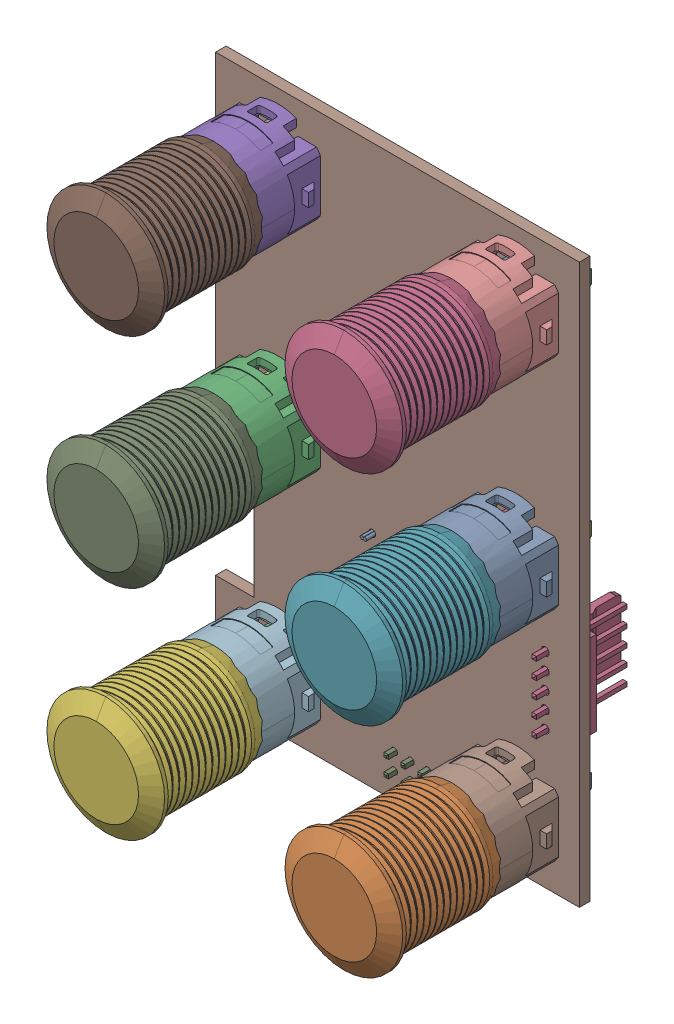
SolidWorks assembly console_left, configuration Default. Lengths in mm.
Overall size (55 84.5 40.9).
107 component instances, 13 part files, 0 mates.
Components (placement in the parent):
- Push Button M16-1: Push Button M16 [Default] at (193 -183 27.15) size (17.8 17.8 33.5)
  - Push Button M16-0-1: Push Button M16-0 [Default] at origin size (17.8 17.8 33.5)
- Push Button M16-2: Push Button M16 [Default] at (193 -216 27.15) size (17.8 17.8 33.5)
  - Push Button M16-0-1: Push Button M16-0 [Default] at origin size (17.8 17.8 33.5)
- Push Button M16-3: Push Button M16 [Default] at (157 -183 27.15) size (17.8 17.8 33.5)
  - Push Button M16-0-1: Push Button M16-0 [Default] at origin size (17.8 17.8 33.5)
- Push Button M16-4: Push Button M16 [Default] at (193 -150 27.15) size (17.8 17.8 33.5)
  - Push Button M16-0-1: Push Button M16-0 [Default] at origin size (17.8 17.8 33.5)
- Push Button M16-5: Push Button M16 [Default] at (157 -150 27.15) size (17.8 17.8 33.5)
  - Push Button M16-0-1: Push Button M16-0 [Default] at origin size (17.8 17.8 33.5)
- Push Button M16-6: Push Button M16 [Default] at (157 -216 27.15) size (17.8 17.8 33.5)
  - Push Button M16-0-1: Push Button M16-0 [Default] at origin size (17.8 17.8 33.5)
- R_1206_3216Metric-1: R_1206_3216Metric [Default] at (189.738 -195.961 -0.05) x (0 1 0) z (0 0 -1) size (3.2 1.6 0.55)
  - R_1206_3216Metric-1-1: R_1206_3216Metric-1 [Default] at origin size (3.2 1.6 0.55)
- R_1206_3216Metric-2: R_1206_3216Metric [Default] at (163.55 -152.908 -0.05) x (-1 0 0) z (0 0 -1) size (3.2 1.6 0.55)
  - R_1206_3216Metric-1-1: R_1206_3216Metric-1 [Default] at origin size (3.2 1.6 0.55)
- R_1206_3216Metric-3: R_1206_3216Metric [Default] at (183.642 -215.9 -0.05) x (0 -1 0) z (0 0 -1) size (3.2 1.6 0.55)
  - R_1206_3216Metric-1-1: R_1206_3216Metric-1 [Default] at origin size (3.2 1.6 0.55)
- R_1206_3216Metric-4: R_1206_3216Metric [Default] at (189.484 -218.974 -0.05) x (0 -1 0) z (0 0 -1) size (3.2 1.6 0.55)
  - R_1206_3216Metric-1-1: R_1206_3216Metric-1 [Default] at origin size (3.2 1.6 0.55)
- R_1206_3216Metric-5: R_1206_3216Metric [Default] at (183.642 -166.09 -0.05) x (0 -1 0) z (0 0 -1) size (3.2 1.6 0.55)
  - R_1206_3216Metric-1-1: R_1206_3216Metric-1 [Default] at origin size (3.2 1.6 0.55)
- R_1206_3216Metric-6: R_1206_3216Metric [Default] at (160.02 -199.491 -0.05) x (0 1 0) z (0 0 -1) size (3.2 1.6 0.55)
  - R_1206_3216Metric-1-1: R_1206_3216Metric-1 [Default] at origin size (3.2 1.6 0.55)
- R_1206_3216Metric-7: R_1206_3216Metric [Default] at (158.75 -165.1 -0.05) x (-1 0 0) z (0 0 -1) size (3.2 1.6 0.55)
  - R_1206_3216Metric-1-1: R_1206_3216Metric-1 [Default] at origin size (3.2 1.6 0.55)
- R_1206_3216Metric-8: R_1206_3216Metric [Default] at (179.451 -149.987 -0.05) x (0 1 0) z (0 0 -1) size (3.2 1.6 0.55)
  - R_1206_3216Metric-1-1: R_1206_3216Metric-1 [Default] at origin size (3.2 1.6 0.55)
- R_1206_3216Metric-9: R_1206_3216Metric [Default] at (183.896 -175.032 -0.05) x (0 1 0) z (0 0 -1) size (3.2 1.6 0.55)
  - R_1206_3216Metric-1-1: R_1206_3216Metric-1 [Default] at origin size (3.2 1.6 0.55)
- C_0603_1608Metric-1: C_0603_1608Metric [Default] at (181.0766 -183.1086 -0.05) x (0 1 0) z (0 0 -1) size (1.6 0.8 0.8)
  - C_0603_1608Metric-2-1: C_0603_1608Metric-2 [Default] at origin size (1.6 0.8 0.8)
- SOIC-14_3.9x8.7mm_P1.27mm-1: SOIC-14_3.9x8.7mm_P1.27mm [Default] at (177.546 -209.296 -0.05) x (0 -1 0) z (0 0 -1) size (6 8.7 1.75)
  - SOIC_14_39x87mm_P127mm-1: SOIC_14_39x87mm_P127mm [Default] at origin size (6 8.7 1.75)
- C_0603_1608Metric-2: C_0603_1608Metric [Default] at (171.704 -207.137 -0.05) x (0 1 0) z (0 0 -1) size (1.6 0.8 0.8)
  - C_0603_1608Metric-2-1: C_0603_1608Metric-2 [Default] at origin size (1.6 0.8 0.8)
- SOT-23-1: SOT-23 [Default] at (185.8495 -220.472 -0.05) x (-1 0 0) z (0 0 -1) size (2.5 3 1.2)
  - SOT_23-1: SOT_23 [Default] at origin size (2.5 3 1.2)
- R_1206_3216Metric-10: R_1206_3216Metric [Default] at (188.24 -185.166 -0.05) x (1 0 0) z (0 0 -1) size (3.2 1.6 0.55)
  - R_1206_3216Metric-1-1: R_1206_3216Metric-1 [Default] at origin size (3.2 1.6 0.55)
- C_1210_3225Metric-1: C_1210_3225Metric [Default] at (161.036 -190.246 -0.05) x (1 0 0) z (0 0 -1) size (3.2 2.5 2.5)
  - C_1210_3225Metric-3-1: C_1210_3225Metric-3 [Default] at origin size (3.2 2.5 2.5)
- R_1206_3216Metric-11: R_1206_3216Metric [Default] at (162.28 -209.296 -0.05) x (-1 0 0) z (0 0 -1) size (3.2 1.6 0.55)
  - R_1206_3216Metric-1-1: R_1206_3216Metric-1 [Default] at origin size (3.2 1.6 0.55)
- R_1206_3216Metric-12: R_1206_3216Metric [Default] at (176.276 -199.136 -0.05) x (0 1 0) z (0 0 -1) size (3.2 1.6 0.55)
  - R_1206_3216Metric-1-1: R_1206_3216Metric-1 [Default] at origin size (3.2 1.6 0.55)
- TestPoint_Loop_D1.80mm_Drill1.0mm_Beaded-1: TestPoint_Loop_D1.80mm_Drill1.0mm_Beaded [Default] at (171.196 -191.643 -0.05) x (-1 0 0) z (0 0 -1) size (2.59 2.54 7.87)
  - TestPoint_Loop_D1_80mm_Drill1_0mm_Beaded_cp-1: TestPoint_Loop_D1_80mm_Drill1_0mm_Beaded_cp [Default] at origin size (2.59 2.54 7.87)
- SOT-23-2: SOT-23 [Default] at (158.242 -171.704 -0.05) x (0 -1 0) z (0 0 -1) size (2.5 3 1.2)
  - SOT_23-1: SOT_23 [Default] at origin size (2.5 3 1.2)
- R_1206_3216Metric-13: R_1206_3216Metric [Default] at (186.436 -215.926 -0.05) x (0 -1 0) z (0 0 -1) size (3.2 1.6 0.55)
  - R_1206_3216Metric-1-1: R_1206_3216Metric-1 [Default] at origin size (3.2 1.6 0.55)
- Molex_KK-254_AE-6410-05A_1x05_P2.54mm_Vertical-1: Molex_KK-254_AE-6410-05A_1x05_P2.54mm_Vertical [Default] at (197.338 -204.216 -0.05) x (0 1 0) z (0 0 -1) size (12.7 5.8 15.26)
  - Molex_AE_6410_05A-1: Molex_AE_6410_05A [Default] at origin size (12.7 5.8 15.26)
- TestPoint_Loop_D1.80mm_Drill1.0mm_Beaded-2: TestPoint_Loop_D1.80mm_Drill1.0mm_Beaded [Default] at (174.498 -194.056 -0.05) x (-1 0 0) z (0 0 -1) size (2.59 2.54 7.87)
  - TestPoint_Loop_D1_80mm_Drill1_0mm_Beaded_cp-1: TestPoint_Loop_D1_80mm_Drill1_0mm_Beaded_cp [Default] at origin size (2.59 2.54 7.87)
- SOT-23-3: SOT-23 [Default] at (198.1685 -185.801 -0.05) x (0 1 0) z (0 0 -1) size (2.5 3 1.2)
  - SOT_23-1: SOT_23 [Default] at origin size (2.5 3 1.2)
- R_1206_3216Metric-14: R_1206_3216Metric [Default] at (174.825 -159.175 -0.05) x (0 1 0) z (0 0 -1) size (3.2 1.6 0.55)
  - R_1206_3216Metric-1-1: R_1206_3216Metric-1 [Default] at origin size (3.2 1.6 0.55)
- PinHeader_2x03_P2.54mm_Vertical-1: PinHeader_2x03_P2.54mm_Vertical [Default] at (174.498 -218.567 -0.05) x (0 -1 0) z (0 0 -1) size (5.08 7.62 11.54)
  - PinHeader_2x03_P254mm_Vertical-1: PinHeader_2x03_P254mm_Vertical [Default] at origin size (5.08 7.62 11.54)
- R_1206_3216Metric-15: R_1206_3216Metric [Default] at (198.374 -155.194 -0.05) x (0 1 0) z (0 0 -1) size (3.2 1.6 0.55)
  - R_1206_3216Metric-1-1: R_1206_3216Metric-1 [Default] at origin size (3.2 1.6 0.55)
- C_0603_1608Metric-3: C_0603_1608Metric [Default] at (168.786 -194.945 -0.05) x (-1 0 0) z (0 0 -1) size (1.6 0.8 0.8)
  - C_0603_1608Metric-2-1: C_0603_1608Metric-2 [Default] at origin size (1.6 0.8 0.8)
- SOT-23-4: SOT-23 [Default] at (182.7045 -160.782 -0.05) x (1 0 0) z (0 0 -1) size (2.5 3 1.2)
  - SOT_23-1: SOT_23 [Default] at origin size (2.5 3 1.2)
- R_1206_3216Metric-16: R_1206_3216Metric [Default] at (162.56 -199.491 -0.05) x (0 1 0) z (0 0 -1) size (3.2 1.6 0.55)
  - R_1206_3216Metric-1-1: R_1206_3216Metric-1 [Default] at origin size (3.2 1.6 0.55)
- SOT-23-5: SOT-23 [Default] at (156.21 -161.544 -0.05) x (0 1 0) z (0 0 -1) size (2.5 3 1.2)
  - SOT_23-1: SOT_23 [Default] at origin size (2.5 3 1.2)
- Murata_NFM61R-1: Murata_NFM61R [Default] at (164.4 -204.5 -1.05) x (-1 0 0) z (0 0 -1) size (6.8 1.6 1.6)
  - Murata_NFM61R-4-1: Murata_NFM61R-4 [Default] at origin size (6.8 1.6 1.6)
- SOT-23-6: SOT-23 [Default] at (162.1305 -220.406 -0.05) x (-1 0 0) z (0 0 -1) size (2.5 3 1.2)
  - SOT_23-1: SOT_23 [Default] at origin size (2.5 3 1.2)
- TSSOP-24_4.4x7.8mm_P0.65mm-1: TSSOP-24_4.4x7.8mm_P0.65mm [Default] at (176.1375 -180.575 -0.05) x (1 0 0) z (0 0 -1) size (6.4 7.8 0.97)
  - TSSOP_24_44x78mm_P065mm-1: TSSOP_24_44x78mm_P065mm [Default] at origin size (6.4 7.8 0.97)
- C_1210_3225Metric-2: C_1210_3225Metric [Default] at (166.37 -190.246 -0.05) x (-1 0 0) z (0 0 -1) size (3.2 2.5 2.5)
  - C_1210_3225Metric-3-1: C_1210_3225Metric-3 [Default] at origin size (3.2 2.5 2.5)
- SOT-23-7: SOT-23 [Default] at (182.9585 -144.272 -0.05) x (1 0 0) z (0 0 -1) size (2.5 3 1.2)
  - SOT_23-1: SOT_23 [Default] at origin size (2.5 3 1.2)
- R_1206_3216Metric-17: R_1206_3216Metric [Default] at (178.689 -199.136 -0.05) x (0 1 0) z (0 0 -1) size (3.2 1.6 0.55)
  - R_1206_3216Metric-1-1: R_1206_3216Metric-1 [Default] at origin size (3.2 1.6 0.55)
- R_1206_3216Metric-18: R_1206_3216Metric [Default] at (165.1 -199.491 -0.05) x (0 1 0) z (0 0 -1) size (3.2 1.6 0.55)
  - R_1206_3216Metric-1-1: R_1206_3216Metric-1 [Default] at origin size (3.2 1.6 0.55)
- R_1206_3216Metric-19: R_1206_3216Metric [Default] at (167.513 -214.757 -0.05) x (0 -1 0) z (0 0 -1) size (3.2 1.6 0.55)
  - R_1206_3216Metric-1-1: R_1206_3216Metric-1 [Default] at origin size (3.2 1.6 0.55)
- R_1206_3216Metric-20: R_1206_3216Metric [Default] at (161.29 -162.306 -0.05) x (1 0 0) z (0 0 -1) size (3.2 1.6 0.55)
  - R_1206_3216Metric-1-1: R_1206_3216Metric-1 [Default] at origin size (3.2 1.6 0.55)
- R_1206_3216Metric-21: R_1206_3216Metric [Default] at (186.563 -194.818 -0.05) x (0 1 0) z (0 0 -1) size (3.2 1.6 0.55)
  - R_1206_3216Metric-1-1: R_1206_3216Metric-1 [Default] at origin size (3.2 1.6 0.55)
- R_1206_3216Metric-22: R_1206_3216Metric [Default] at (154.178 -171.196 -0.05) x (0 -1 0) z (0 0 -1) size (3.2 1.6 0.55)
  - R_1206_3216Metric-1-1: R_1206_3216Metric-1 [Default] at origin size (3.2 1.6 0.55)
- R_1206_3216Metric-23: R_1206_3216Metric [Default] at (158.75 -167.767 -0.05) x (-1 0 0) z (0 0 -1) size (3.2 1.6 0.55)
  - R_1206_3216Metric-1-1: R_1206_3216Metric-1 [Default] at origin size (3.2 1.6 0.55)
- R_1206_3216Metric-24: R_1206_3216Metric [Default] at (197.586 -189.992 -0.05) x (1 0 0) z (0 0 -1) size (3.2 1.6 0.55)
  - R_1206_3216Metric-1-1: R_1206_3216Metric-1 [Default] at origin size (3.2 1.6 0.55)
- SOIC-8_3.9x4.9mm_P1.27mm-1: SOIC-8_3.9x4.9mm_P1.27mm [Default] at (170.753 -199.39 -0.05) x (-1 0 0) z (0 0 -1) size (6 4.9 1.75)
  - SOIC_8_39x49mm_P127mm-1: SOIC_8_39x49mm_P127mm [Default] at origin size (6 4.9 1.75)
- R_1206_3216Metric-25: R_1206_3216Metric [Default] at (179.451 -144.653 -0.05) x (0 1 0) z (0 0 -1) size (3.2 1.6 0.55)
  - R_1206_3216Metric-1-1: R_1206_3216Metric-1 [Default] at origin size (3.2 1.6 0.55)
- R_1206_3216Metric-26: R_1206_3216Metric [Default] at (196.85 -175.006 -0.05) x (-1 0 0) z (0 0 -1) size (3.2 1.6 0.55)
  - R_1206_3216Metric-1-1: R_1206_3216Metric-1 [Default] at origin size (3.2 1.6 0.55)
- R_1206_3216Metric-27: R_1206_3216Metric [Default] at (164.719 -214.757 -0.05) x (0 1 0) z (0 0 -1) size (3.2 1.6 0.55)
  - R_1206_3216Metric-1-1: R_1206_3216Metric-1 [Default] at origin size (3.2 1.6 0.55)
- console_left_PCB-1: console_left_PCB [Default] at origin size (55 84.5 1.6)
